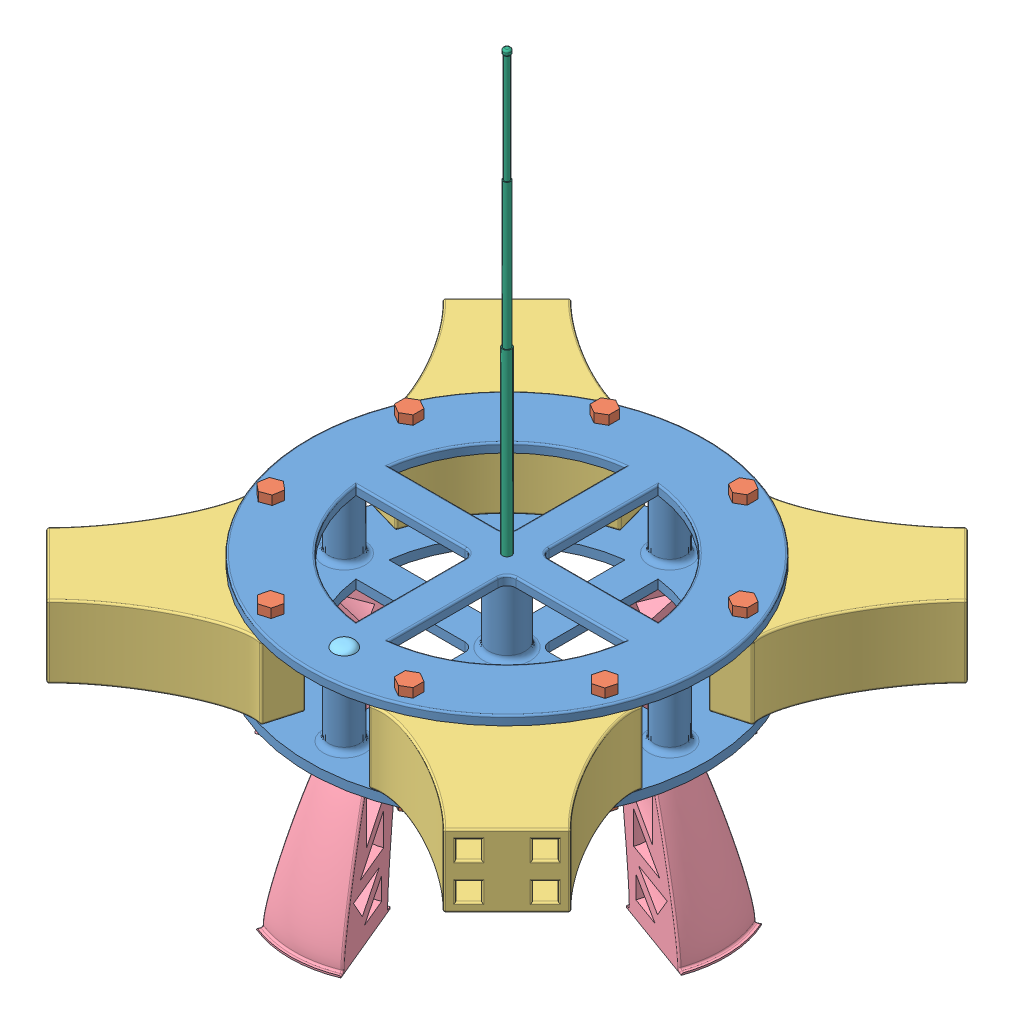
SolidWorks assembly Base-Connector-Assembly, configuration Default. Lengths in mm.
Overall size (752.9 953.82 752.71).
19 component instances, 6 part files, 40 mates.
Components (placement in the parent):
- Drone_BaseF-1: Drone_BaseF [Default] at (185.4655 243.7928 430.4737) size (558.8 129.54 558.8)
- Bolt-1: Bolt [Default] at (-49.1999 243.7928 527.6753) x (0.986044 0 0.166487) z (-0.166487 0 0.986044) size (26.4 152.4 30.48)
- Bolt-2: Bolt [Default] at (88.2639 243.7928 665.1391) x (0.691609 0 -0.722272) z (0.722272 0 0.691609) size (26.4 152.4 30.48)
- Bolt-3: Bolt [Default] at (-49.1999 243.7928 333.2721) size (26.4 152.4 30.48)
- Bolt-4: Bolt [Default] at (88.2639 243.7928 195.8083) size (26.4 152.4 30.48)
- Bolt-5: Bolt [Default] at (282.6671 243.7928 195.8083) size (26.4 152.4 30.48)
- Bolt-6: Bolt [Default] at (420.1309 243.7928 333.2721) size (26.4 152.4 30.48)
- Bolt-7: Bolt [Default] at (420.1309 243.7928 527.6753) x (0.258858 0 0.965915) z (-0.965915 0 0.258858) size (26.4 152.4 30.48)
- Bolt-8: Bolt [Default] at (282.6671 243.7928 665.1391) size (26.4 152.4 30.48)
- Drone_Connector-2: Drone_Connector [Default] at (185.4655 256.4928 430.4737) size (312.47 116.72 314.78)
- Drone_Connector-3: Drone_Connector [Default] at (185.4655 256.4928 430.4737) x (0 0 -1) z (1 0 0) size (312.47 116.72 314.78)
- Drone_Connector-4: Drone_Connector [Default] at (185.4655 358.0928 430.4737) x (0 0 1) z (1 0 0) size (312.47 116.72 314.78)
- Drone_Connector-5: Drone_Connector [Default] at (185.4655 256.4928 430.4737) x (0 0 1) z (-1 0 0) size (312.47 116.72 314.78)
- Drone_LandingGear-5: Drone_LandingGear [Default] at (-101.6635 31.936 372.7632) x (0.910912 0 0.4126) z (-0.4126 0 0.910912) size (160.77 212.14 149.82)
- Drone_LandingGear-6: Drone_LandingGear [Default] at (131.2263 31.936 719.593) x (0.37996 0 -0.925003) z (0.925003 0 0.37996) size (160.77 212.14 149.82)
- Drone_LandingGear-7: Drone_LandingGear [Default] at (476.7222 31.936 480.6309) x (-0.93978 0 -0.341781) z (0.341781 0 -0.93978) size (160.77 212.14 149.82)
- Drone_LandingGear-8: Drone_LandingGear [Default] at (239.219 31.936 141.0888) x (-0.375406 0 0.92686) z (-0.92686 0 -0.375406) size (160.77 212.14 149.82)
- Drone_LEDindicator-1: Drone_LEDindicator [Default] at (187.5441 370.7928 657.6139) x (0.818355 0 -0.574713) z (0.574713 0 0.818355) size (30.48 9.04 30.48)
- Drone_ReceiverAntenna-2: Drone_ReceiverAntenna [Default] at (185.4655 368.2528 430.4737) x (0.079137 0 -0.996864) z (0.996864 0 0.079137) size (12.7 617.22 12.7)
Mates (geometry in assembly coordinates):
- Concentric1: concentric aligned: cylinder of Drone_BaseF-1 through (-49.1999 370.7928 527.6753) axis (0 -1 0) radius 10.16; cylinder of Bolt-1 through (-49.1999 370.7928 527.6753) axis (0 -1 0) radius 10.16
- Coincident2: coincident anti-aligned: plane of Drone_BaseF-1 through (185.4655 370.7928 430.4737) normal (0 1 0); plane of Bolt-1 through (-49.1999 370.7928 527.6753) normal (0 -1 0)
- Concentric2: concentric aligned: cylinder of Drone_BaseF-1 through (88.2639 370.7928 665.1391) axis (0 -1 0) radius 10.16; cylinder of Bolt-2 through (88.2639 370.7928 665.1391) axis (0 -1 0) radius 10.16
- Coincident3: coincident anti-aligned: plane of Drone_BaseF-1 through (185.4655 370.7928 430.4737) normal (0 1 0); plane of Bolt-2 through (88.2639 370.7928 665.1391) normal (0 -1 0)
- Concentric3: concentric aligned: cylinder of Bolt-1 through (-49.1999 370.7928 527.6753) axis (0 -1 0) radius 10.16; cylinder of Drone_Connector-2 through (-49.1999 358.0928 527.6753) axis (0 -1 0) radius 10.16
- Coincident4: coincident anti-aligned: plane of Drone_BaseF-1 through (-93.9345 358.0928 151.0737) normal (0 -1 0); plane of Drone_Connector-2 through (185.4655 358.0928 430.4737) normal (0 1 0)
- Concentric4: concentric aligned: cylinder of Bolt-2 through (88.2639 370.7928 665.1391) axis (0 -1 0) radius 10.16; cylinder of Drone_Connector-2 through (88.2639 358.0928 665.1391) axis (0 -1 0) radius 10.16
- Concentric5: concentric aligned: cylinder of Drone_BaseF-1 through (282.6671 370.7928 665.1391) axis (0 -1 0) radius 10.16; cylinder of Bolt-8 through (282.6671 370.7928 665.1391) axis (0 -1 0) radius 10.16
- Coincident5: coincident anti-aligned: plane of Drone_BaseF-1 through (185.4655 370.7928 430.4737) normal (0 1 0); plane of Bolt-8 through (282.6671 370.7928 665.1391) normal (0 -1 0)
- Coincident6: coincident anti-aligned: plane of Drone_BaseF-1 through (185.4655 370.7928 430.4737) normal (0 1 0); plane of Bolt-7 through (420.1309 370.7928 527.6753) normal (0 -1 0)
- Concentric6: concentric aligned: cylinder of Drone_BaseF-1 through (420.1309 370.7928 527.6753) axis (0 -1 0) radius 10.16; cylinder of Bolt-7 through (420.1309 370.7928 527.6753) axis (0 -1 0) radius 10.16
- Concentric7: concentric aligned: cylinder of Drone_BaseF-1 through (420.1309 370.7928 333.2721) axis (0 -1 0) radius 10.16; cylinder of Bolt-6 through (420.1309 370.7928 333.2721) axis (0 -1 0) radius 10.16
- Coincident7: coincident anti-aligned: plane of Drone_BaseF-1 through (185.4655 370.7928 430.4737) normal (0 1 0); plane of Bolt-6 through (420.1309 370.7928 333.2721) normal (0 -1 0)
- Concentric8: concentric aligned: cylinder of Drone_BaseF-1 through (282.6671 370.7928 195.8083) axis (0 -1 0) radius 10.16; cylinder of Bolt-5 through (282.6671 370.7928 195.8083) axis (0 -1 0) radius 10.16
- Coincident8: coincident anti-aligned: plane of Drone_BaseF-1 through (185.4655 370.7928 430.4737) normal (0 1 0); plane of Bolt-5 through (282.6671 370.7928 195.8083) normal (0 -1 0)
- Concentric9: concentric aligned: cylinder of Drone_BaseF-1 through (88.2639 370.7928 195.8083) axis (0 -1 0) radius 10.16; cylinder of Bolt-4 through (88.2639 370.7928 195.8083) axis (0 -1 0) radius 10.16
- Coincident9: coincident anti-aligned: plane of Drone_BaseF-1 through (185.4655 370.7928 430.4737) normal (0 1 0); plane of Bolt-4 through (88.2639 370.7928 195.8083) normal (0 -1 0)
- Concentric10: concentric aligned: cylinder of Drone_BaseF-1 through (-49.1999 370.7928 333.2721) axis (0 -1 0) radius 10.16; cylinder of Bolt-3 through (-49.1999 370.7928 333.2721) axis (0 -1 0) radius 10.16
- Coincident10: coincident anti-aligned: plane of Drone_BaseF-1 through (185.4655 370.7928 430.4737) normal (0 1 0); plane of Bolt-3 through (-49.1999 370.7928 333.2721) normal (0 -1 0)
- Concentric11: concentric aligned: cylinder of Bolt-8 through (282.6671 370.7928 665.1391) axis (0 -1 0) radius 10.16; cylinder of Drone_Connector-3 through (282.6671 358.0928 665.1391) axis (0 -1 0) radius 10.16
- Concentric12: concentric aligned: cylinder of Bolt-7 through (420.1309 370.7928 527.6753) axis (0 -1 0) radius 10.16; cylinder of Drone_Connector-3 through (420.1309 358.0928 527.6753) axis (0 -1 0) radius 10.16
- Coincident11: coincident anti-aligned: plane of Drone_BaseF-1 through (-93.9345 358.0928 151.0737) normal (0 -1 0); plane of Drone_Connector-3 through (185.4655 358.0928 430.4737) normal (0 1 0)
- Concentric13: concentric anti-aligned: cylinder of Bolt-5 through (282.6671 370.7928 195.8083) axis (0 -1 0) radius 10.16; cylinder of Drone_Connector-4 through (282.6671 256.4928 195.8083) axis (0 1 0) radius 10.16
- Concentric14: concentric anti-aligned: cylinder of Bolt-6 through (420.1309 370.7928 333.2721) axis (0 -1 0) radius 10.16; cylinder of Drone_Connector-4 through (420.1309 256.4928 333.2721) axis (0 1 0) radius 10.16
- Coincident12: coincident anti-aligned: plane of Drone_BaseF-1 through (-93.9345 358.0928 151.0737) normal (0 -1 0); plane of Drone_Connector-4 through (185.4655 358.0928 430.4737) normal (0 1 0)
- Concentric16: concentric aligned: cylinder of Bolt-3 through (-49.1999 370.7928 333.2721) axis (0 -1 0) radius 10.16; cylinder of Drone_Connector-5 through (-49.1999 358.0928 333.2721) axis (0 -1 0) radius 10.16
- Concentric17: concentric aligned: cylinder of Bolt-4 through (88.2639 370.7928 195.8083) axis (0 -1 0) radius 10.16; cylinder of Drone_Connector-5 through (88.2639 358.0928 195.8083) axis (0 -1 0) radius 10.16
- Coincident13: coincident anti-aligned: plane of Drone_BaseF-1 through (-93.9345 358.0928 151.0737) normal (0 -1 0); plane of Drone_Connector-5 through (185.4655 358.0928 430.4737) normal (0 1 0)
- Concentric22: concentric aligned: cylinder of Drone_BaseF-1 through (185.4655 241.2528 620.9737) axis (0 1 0) radius 3.175; cylinder of Drone_LandingGear-6 through (185.4655 241.2528 620.9737) axis (0 1 0) radius 3.175
- Coincident20: coincident anti-aligned: plane of Drone_BaseF-1 through (185.4655 241.2528 620.9737) normal (0 -1 0); plane of Drone_LandingGear-6 through (185.4655 241.2528 620.9737) normal (0 1 0)
- Concentric23: concentric aligned: cylinder of Drone_BaseF-1 through (375.9655 241.2528 430.4737) axis (0 1 0) radius 3.175; cylinder of Drone_LandingGear-7 through (375.9655 241.2528 430.4737) axis (0 1 0) radius 3.175
- Coincident21: coincident anti-aligned: plane of Drone_BaseF-1 through (375.9655 241.2528 430.4737) normal (0 -1 0); plane of Drone_LandingGear-7 through (375.9655 241.2528 430.4737) normal (0 1 0)
- Concentric24: concentric aligned: cylinder of Drone_BaseF-1 through (185.4655 241.2528 239.9737) axis (0 1 0) radius 3.175; cylinder of Drone_LandingGear-8 through (185.4655 241.2528 239.9737) axis (0 1 0) radius 3.175
- Coincident22: coincident anti-aligned: plane of Drone_BaseF-1 through (185.4655 241.2528 239.9737) normal (0 -1 0); plane of Drone_LandingGear-8 through (185.4655 241.2528 239.9737) normal (0 1 0)
- Concentric25: concentric aligned: cylinder of Drone_BaseF-1 through (-5.0345 241.2528 430.4737) axis (0 1 0) radius 3.175; cylinder of Drone_LandingGear-5 through (-5.0345 241.2528 430.4737) axis (0 1 0) radius 3.175
- Coincident23: coincident anti-aligned: plane of Drone_BaseF-1 through (-5.0345 241.2528 430.4737) normal (0 -1 0); plane of Drone_LandingGear-5 through (-5.0345 241.2528 430.4737) normal (0 1 0)
- Concentric26: concentric anti-aligned: cylinder of Drone_BaseF-1 through (185.4655 368.2528 659.0737) axis (0 1 0) radius 2.54; cylinder of Drone_LEDindicator-1 through (185.4655 377.1428 659.0737) axis (0 -1 0) radius 2.54
- Coincident24: coincident anti-aligned: plane of Drone_BaseF-1 through (185.4655 368.2528 659.0737) normal (0 1 0); plane of Drone_LEDindicator-1 through (187.5441 368.2528 657.6139) normal (0 -1 0)
- Concentric27: concentric anti-aligned: cylinder of Drone_BaseF-1 through (185.4655 368.2528 430.4737) axis (0 1 0) radius 6.35; cylinder of Drone_ReceiverAntenna-2 through (185.4655 622.2528 430.4737) axis (0 -1 0) radius 6.35
- Coincident25: coincident anti-aligned: plane of Drone_BaseF-1 through (185.4655 368.2528 430.4737) normal (0 1 0); plane of Drone_ReceiverAntenna-2 through (185.4655 368.2528 430.4737) normal (0 -1 0)
